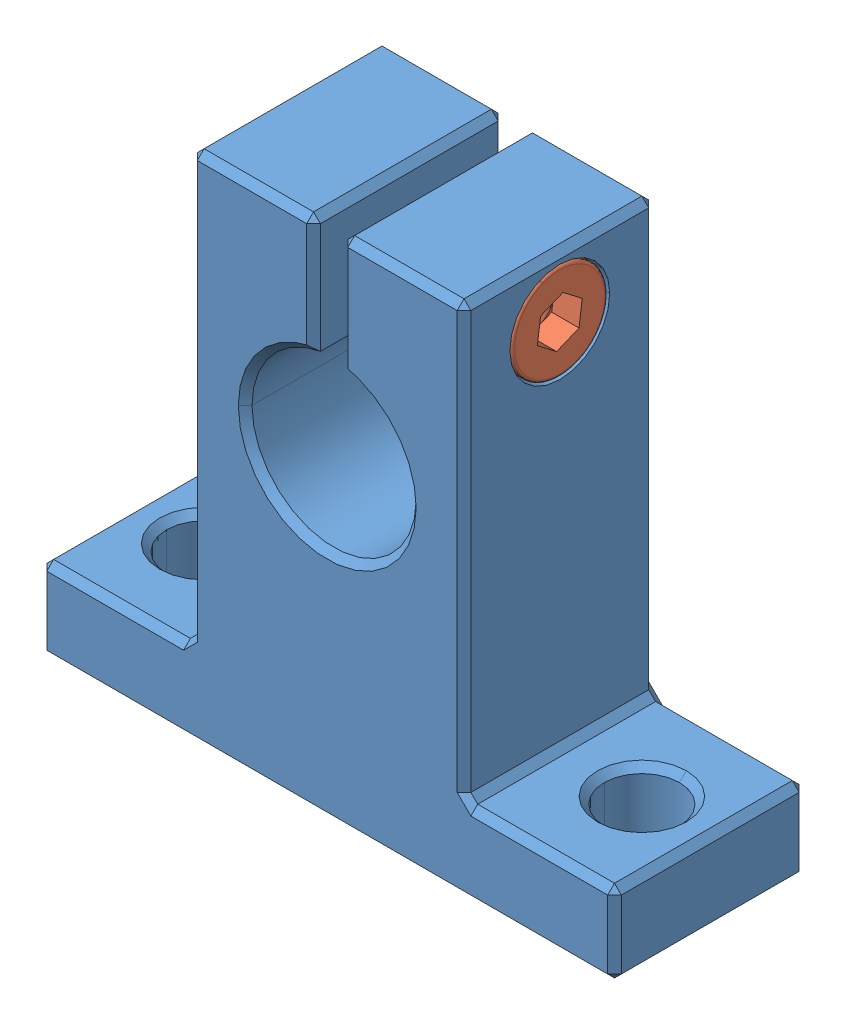
SolidWorks assembly SK12, configuration Default. Lengths in mm.
Overall size (42 37.6 14).
3 component instances, 2 part files, 0 mates.
Components (placement in the parent):
- SK12.STEP-1: SK12.STEP [Default] at origin size (42 37.6 14)
  - Shaft support SK12.STEP-1: Shaft support SK12.STEP [Default] at (-5.6953 6.0163 42) size (42 37.5 14)
  - m4x16.STEP-1: m4x16.STEP [Default] at (4.3047 16.0441 42) x (-1 0 0) z (0 0.924225 0.381849) size (20 7 7)
